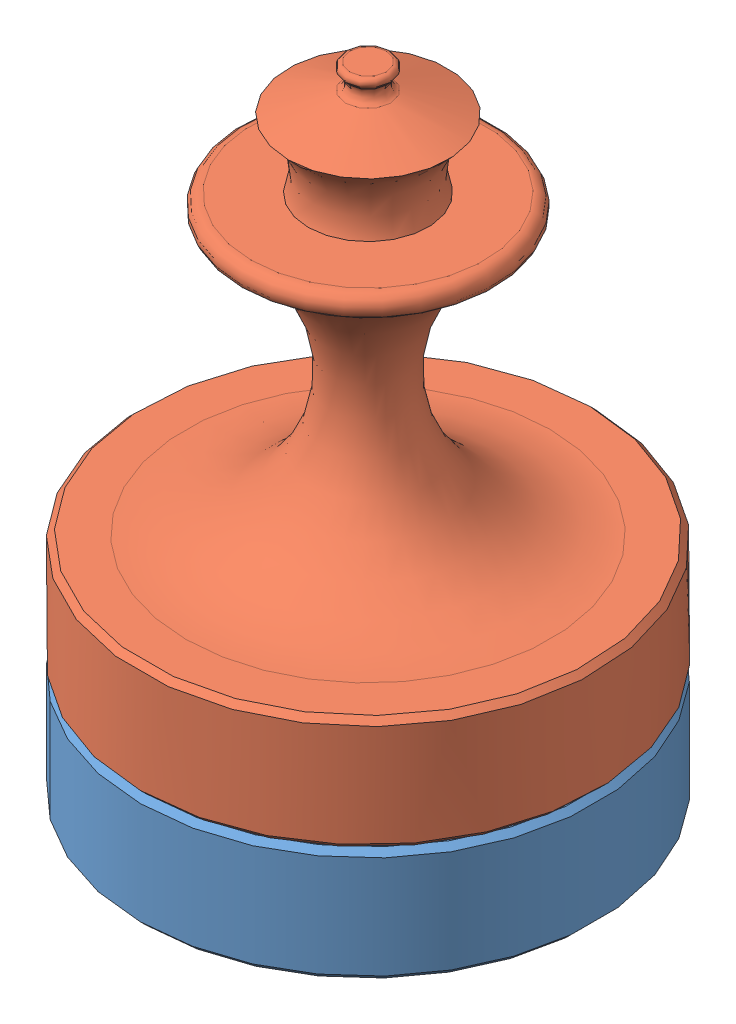
SolidWorks assembly empilage_pions_double, configuration Default. Lengths in mm.
Overall size (200 280 200).
2 component instances, 2 part files, 1 mates.
Components (placement in the parent):
- Pion-1: Pion [Default] at (12.2803 -6.2278 -19.2337) size (200 50 200)
- roi_reine-1: roi_reine [Default] at (12.2803 93.7722 -19.2337) size (200 230 200)
Mates (geometry in assembly coordinates):
- Coïncidente3: coincident anti-aligned: plane of Pion-1 through (12.2803 43.7722 -19.2337) normal (0 1 0); plane of ? through (12.2803 93.7722 -19.2337) normal (0 -1 0)
